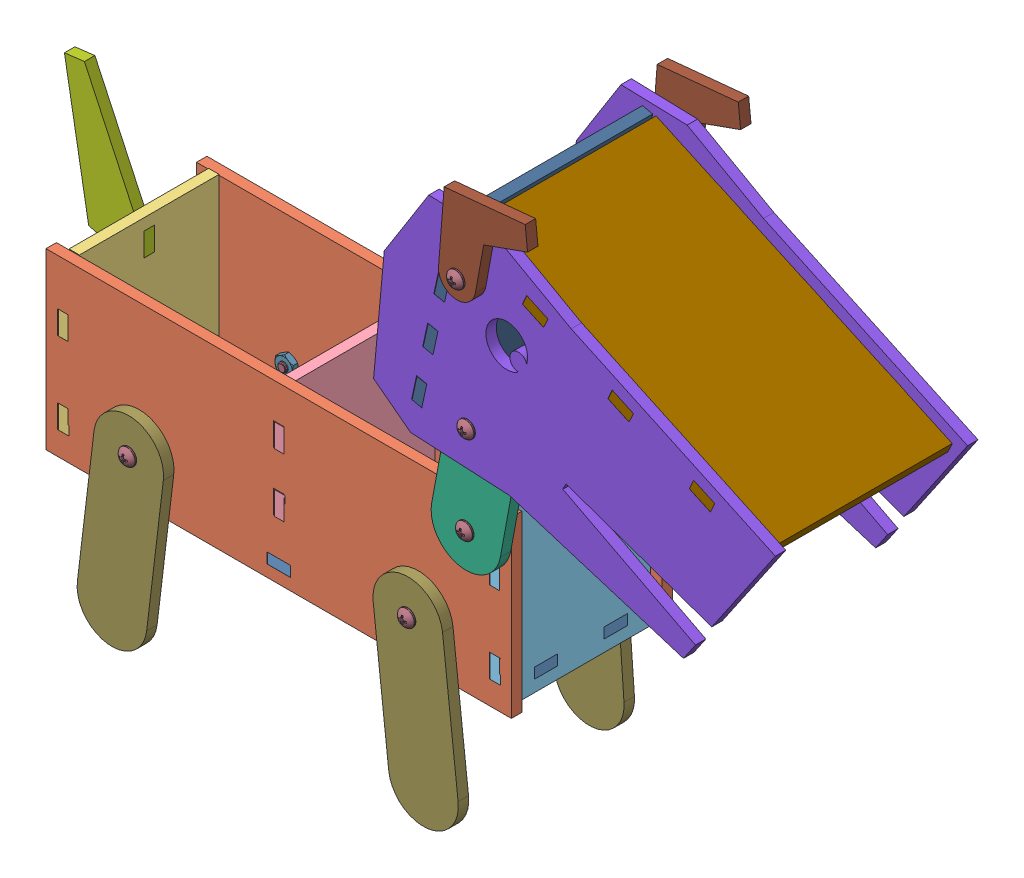
SolidWorks assembly Doggie Lamp, configuration Default. Lengths in mm.
Overall size (449.3 333.43 128.68).
39 component instances, 14 part files, 85 mates.
Components (placement in the parent):
- Bottom-2: Bottom [Default] at (-28.2782 -5.676 3.5153) size (241.25 5.69 87.58)
- Body Sides-5: Body Sides [Default] at (-28.7862 51.4486 41.6153) x (1 0 0) z (0 -1 0) size (254 5.69 95.09)
- Body Sides-6: Body Sides [Default] at (-28.5322 51.4486 -40.2743) x (1 0 0) z (0 -1 0) size (254 5.69 95.09)
- Back-2: Back [Default] at (-143.2132 51.474 3.5153) x (0 0 1) z (0 -1 0) size (87.58 5.69 95.5)
- Middle-2: Middle [Default] at (-25.4334 57.1636 3.5153) x (0 0 1) z (0 -1 0) size (87.58 5.69 89.26)
- Front-2: Front [Default] at (92.3464 51.4486 3.5153) x (0 0 1) z (0 -1 0) size (87.58 5.69 95.5)
- Neck-3: Neck [Default] at (91.28 126.961 -45.9639) x (0.98334 -0.181777 0) z (-0.181777 -0.98334 0) size (38.1 5.69 88.9)
- Neck-4: Neck [Default] at (79.2344 63.1735 52.9945) x (0.98334 -0.181777 0) z (0.181777 0.98334 0) size (38.1 5.69 88.9)
- Tail-1: Tail [Default] at (-148.9028 70.778 0.6705) x (1 0 0) z (0 -1 0) size (43.46 5.69 82.95)
- Head-1: Head [Default] at (139.8428 140.5016 52.9945) x (0.977251 -0.212085 0) z (-0.212085 -0.977251 0) size (216.62 5.69 123.24)
- Head-2: Head [Default] at (140.0968 140.5016 -51.6535) x (0.977251 -0.212085 0) z (-0.212085 -0.977251 0) size (216.62 5.69 123.24)
- Head Top 2-1: Head Top 2 [Default] at (168.1653 174.1819 3.5153) x (0.909157 -0.416453 0) z (0 0 1) size (177.8 5.69 110.34)
- Head Back-1: Head Back [Default] at (68.5938 156.9044 3.5153) x (0 0 1) z (-0.212085 -0.977251 0) size (110.34 5.69 114.3)
- Ears-3: Ears [Default] at (85.6371 198.1656 58.6841) x (0.98367 -0.179982 0) z (-0.179982 -0.98367 0) size (46.25 5.69 60.22)
- Ears-4: Ears [Default] at (85.8911 198.1656 -57.3431) x (0.98367 -0.179982 0) z (-0.179982 -0.98367 0) size (46.25 5.69 60.22)
- Legs-5: Legs [Default] at (-105.8128 -5.0499 47.3049) x (0.992872 -0.119184 0) z (-0.119184 -0.992872 0) size (38.1 5.69 114.3)
- Legs-6: Legs [Default] at (50.8253 -4.7497 47.3049) x (0.993764 0.111505 0) z (0.111505 -0.993764 0) size (38.1 5.69 114.3)
- Legs-7: Legs [Default] at (50.3495 -4.8722 -45.9639) x (0.997441 0.071495 0) z (0.071495 -0.997441 0) size (38.1 5.69 114.3)
- Legs-8: Legs [Default] at (-105.0938 -5.0649 -45.9639) x (0.995565 -0.094071 0) z (-0.094071 -0.995565 0) size (38.1 5.69 114.3)
- Bolt-1: Bolt [90279A830] at (-104.9862 13.3486 37.1195) size (9.12 9.12 19.48)
- Nut-1: Nut [90545A111] at (-104.9862 13.3486 41.6153) size (9.53 11 3.7)
- Bolt-2: Bolt [90279A830] at (-104.7322 13.3486 -30.0889) x (-0.714681 0.699451 0) z (0 0 -1) size (9.12 9.12 19.48)
- Bolt-3: Bolt [90279A830] at (47.6678 13.3486 -30.0889) x (-0.97579 0.218712 0) z (0 0 -1) size (9.12 9.12 19.48)
- Bolt-4: Bolt [90279A830] at (47.4138 13.3486 37.1195) size (9.12 9.12 19.48)
- Nut-2: Nut [90545A111] at (47.6678 13.3486 -31.4097) size (9.53 11 3.7)
- Nut-3: Nut [90545A111] at (47.4138 13.3486 41.6153) size (9.53 11 3.7)
- Nut-4: Nut [90545A111] at (-104.7322 13.3486 -31.4097) size (9.53 11 3.7)
- Bolt-5: Bolt [90279A830] at (79.1638 70.3398 37.1195) size (9.12 9.12 19.48)
- Bolt-6: Bolt [90279A830] at (79.4178 70.3398 -30.0889) x (0.016738 -0.99986 0) z (0 0 -1) size (9.12 9.12 19.48)
- Nut-5: Nut [90545A111] at (79.4178 70.3398 -31.4097) size (9.53 11 3.7)
- Nut-6: Nut [90545A111] at (79.1638 70.3398 41.6153) size (9.53 11 3.7)
- Bolt-7: Bolt [90279A830] at (85.8422 124.4841 -35.7785) x (-0.858966 0.512033 0) z (0 0 -1) size (9.12 9.12 19.48)
- Nut-7: Nut [90545A111] at (85.8422 124.4841 -37.0993) size (9.53 11 3.7)
- Bolt-8: Bolt [90279A830] at (85.5882 124.4841 42.8091) size (9.12 9.12 19.48)
- Nut-8: Nut [90545A111] at (85.5882 124.4841 47.3049) size (9.53 11 3.7)
- Bolt-9: Bolt [90279A830] at (85.6371 198.1656 48.4987) size (9.12 9.12 19.48)
- Nut-9: Nut [90545A111] at (85.6371 198.1656 52.9945) size (9.53 11 3.7)
- Bolt-10: Bolt [90279A830] at (85.8911 198.1656 -41.4681) x (0.959763 0.280811 0) z (0 0 -1) size (9.12 9.12 19.48)
- Nut-10: Nut [90545A111] at (85.8911 198.1656 -42.7889) size (9.53 11 3.7)
Mates (geometry in assembly coordinates):
- Coincident44: coincident anti-aligned: plane of Bottom-2 through (-35.0092 0.0136 41.6153) normal (0 0 1); plane of Body Sides-5 through (-155.7862 114.9486 41.6153) normal (0 0 -1)
- Coincident45: coincident anti-aligned: plane of Bottom-2 through (-101.8112 0.0136 41.6153) normal (-1 0 0); plane of Body Sides-5 through (-101.8112 -5.7014 47.3049) normal (1 0 0)
- Coincident46: coincident anti-aligned: plane of Bottom-2 through (-143.2132 0.0136 -34.5847) normal (0 1 0); plane of Body Sides-5 through (-101.8112 0.0136 47.3049) normal (0 -1 0)
- Coincident47: coincident anti-aligned: plane of Bottom-2 through (-101.8112 0.0136 -34.5847) normal (0 0 -1); plane of Body Sides-6 through (-155.5322 114.9486 -34.5847) normal (0 0 1)
- Coincident48: coincident anti-aligned: plane of Bottom-2 through (44.4928 0.0136 -34.5847) normal (1 0 0); plane of Body Sides-6 through (44.4928 -5.7014 -34.5847) normal (-1 0 0)
- Coincident49: coincident anti-aligned: plane of Bottom-2 through (-143.2132 0.0136 -34.5847) normal (0 1 0); plane of Body Sides-6 through (44.4928 0.0136 -34.5847) normal (0 -1 0)
- Coincident50: coincident anti-aligned: plane of Bottom-2 through (-143.2132 0.0136 16.2153) normal (-1 0 0); plane of Back-2 through (-143.2132 114.974 -34.5847) normal (1 0 0)
- Coincident51: coincident anti-aligned: plane of Bottom-2 through (-143.2132 -5.676 -34.5847) normal (0 -1 0); plane of Back-2 through (-148.9028 -5.676 -21.8847) normal (0 1 0)
- Coincident52: coincident anti-aligned: plane of Bottom-2 through (-143.2132 0.0136 -9.1847) normal (0 0 1); plane of Back-2 through (-148.9028 0.039 -9.1847) normal (0 0 -1)
- Coincident53: coincident anti-aligned: plane of Bottom-2 through (-143.2132 0.0136 -34.5847) normal (0 1 0); plane of Middle-2 through (-31.123 0.0136 41.6153) normal (0 -1 0)
- Coincident54: coincident anti-aligned: plane of Bottom-2 through (-25.4334 0.0136 9.8653) normal (-1 0 0); plane of Middle-2 through (-25.4334 114.3136 -34.5847) normal (1 0 0)
- Coincident55: coincident anti-aligned: plane of Bottom-2 through (-31.123 0.0136 9.8653) normal (0 0 -1); plane of Middle-2 through (-31.123 0.0136 9.8653) normal (0 0 1)
- Coincident56: coincident anti-aligned: plane of Bottom-2 through (86.6568 0.0136 16.2153) normal (1 0 0); plane of Front-2 through (86.6568 114.9486 -34.5847) normal (-1 0 0)
- Coincident57: coincident anti-aligned: plane of Bottom-2 through (-143.2132 0.0136 -34.5847) normal (0 1 0); plane of Front-2 through (86.6568 0.0136 -21.8847) normal (0 -1 0)
- Coincident58: coincident anti-aligned: plane of Body Sides-6 through (-155.5322 114.9486 -34.5847) normal (0 0 1); plane of Front-2 through (86.6568 57.7986 -34.5847) normal (0 0 -1)
- Coincident59: coincident anti-aligned: plane of Body Sides-6 through (-155.5322 114.9486 -40.2743) normal (0 0 -1); plane of Neck-3 through (88.6521 120.2935 -40.2743) normal (0 0 1)
- Coincident60: coincident anti-aligned: plane of Body Sides-5 through (-155.7862 114.9486 47.3049) normal (0 0 1); plane of Neck-4 through (79.1638 70.3398 47.3049) normal (0 0 -1)
- Parallel1: parallel aligned: plane of Neck-3 through (60.6852 73.8027 -40.2743) normal (-0.98334 0.181777 0); plane of Neck-4 through (69.6655 123.7564 47.3049) normal (-0.98334 0.181777 0)
- Coincident62: coincident anti-aligned: plane of Back-2 through (-148.9028 114.974 -34.5847) normal (-1 0 0); plane of Tail-1 through (-148.9028 77.128 6.3601) normal (1 0 0)
- Coincident63: coincident anti-aligned: plane of Back-2 through (-143.2132 77.128 6.3601) normal (0 0 -1); plane of Tail-1 through (-143.2132 64.428 6.3601) normal (0 0 1)
- Coincident64: coincident anti-aligned: plane of Back-2 through (-143.2132 64.428 0.6705) normal (0 1 0); plane of Tail-1 through (-148.9028 64.428 6.3601) normal (0 -1 0)
- Coincident65: coincident anti-aligned: plane of Neck-4 through (79.1638 70.3398 52.9945) normal (0 0 1); plane of Head-1 through (-102.7515 180.5017 52.9945) normal (0 0 -1)
- Coincident66: coincident anti-aligned: plane of Neck-3 through (88.6521 120.2935 -45.9639) normal (0 0 -1); plane of Head-2 through (-102.4975 180.5017 -45.9639) normal (0 0 1)
- Parallel2: parallel aligned: plane of Head-1 through (38.5262 167.5336 58.6841) normal (-0.995814 0.091407 0); plane of Head-2 through (38.7802 167.5336 -45.9639) normal (-0.995814 0.091407 0)
- Coincident72: coincident anti-aligned: plane of Head-1 through (-55.7889 283.0255 58.6841) normal (-0.416453 -0.909157 0); plane of Head Top 2-1 through (83.9375 219.0218 -45.9639) normal (0.416453 0.909157 0)
- Coincident73: coincident anti-aligned: plane of Head-1 through (173.6831 53.8768 58.6841) normal (-0.909157 0.416453 0); plane of Head Top 2-1 through (220.6456 156.4006 52.9945) normal (0.909157 -0.416453 0)
- Coincident74: coincident anti-aligned: plane of Head-1 through (-102.7515 180.5017 52.9945) normal (0 0 -1); plane of Head Top 2-1 through (209.0994 161.6896 52.9945) normal (0 0 1)
- Coincident75: coincident anti-aligned: plane of Head-2 through (60.2287 145.1865 -45.9639) normal (0.977251 -0.212085 0); plane of Head Back-1 through (76.5011 220.1666 -45.9639) normal (-0.977251 0.212085 0)
- Coincident76: coincident anti-aligned: plane of Head-2 through (-102.4975 180.5017 -45.9639) normal (0 0 1); plane of Head Back-1 through (58.0827 135.2982 -45.9639) normal (0 0 -1)
- Coincident77: coincident anti-aligned: plane of Head-2 through (-92.4689 226.7116 -45.9639) normal (-0.212085 -0.977251 0); plane of Head Back-1 through (70.2573 191.3963 -45.9639) normal (0.212085 0.977251 0)
- Coincident78: coincident anti-aligned: plane of Head-1 through (-102.7515 180.5017 58.6841) normal (0 0 1); plane of Ears-3 through (85.6371 198.1656 58.6841) normal (0 0 -1)
- Concentric9: concentric aligned: cylinder of Head-1 through (85.6371 198.1656 58.6841) axis (0 0 -1) radius 2.413; cylinder of Ears-3 through (85.6371 198.1656 64.3737) axis (0 0 -1) radius 2.413
- Coincident79: coincident anti-aligned: plane of Head-2 through (-102.4975 180.5017 -51.6535) normal (0 0 -1); plane of Ears-4 through (85.8911 198.1656 -51.6535) normal (0 0 1)
- Concentric10: concentric aligned: cylinder of Head-2 through (85.8911 198.1656 -45.9639) axis (0 0 -1) radius 2.413; cylinder of Ears-4 through (85.8911 198.1656 -51.6535) axis (0 0 -1) radius 2.413
- Parallel3: parallel aligned: plane of Ears-3 through (75.6431 199.9942 64.3737) normal (-0.996994 0.077481 0); plane of Ears-4 through (75.8971 199.9942 -51.6535) normal (-0.996994 0.077481 0)
- Coincident81: coincident anti-aligned: plane of Body Sides-5 through (-155.7862 114.9486 47.3049) normal (0 0 1); plane of Legs-5 through (-104.9862 13.3486 47.3049) normal (0 0 -1)
- Concentric11: concentric anti-aligned: cylinder of Body Sides-5 through (-104.9862 13.3486 47.3049) axis (0 0 -1) radius 2.413; cylinder of Legs-5 through (-104.9862 13.3486 47.3049) axis (0 0 1) radius 2.413
- Concentric12: concentric anti-aligned: cylinder of Body Sides-5 through (47.4138 13.3486 47.3049) axis (0 0 -1) radius 2.413; cylinder of Legs-6 through (47.4138 13.3486 47.3049) axis (0 0 1) radius 2.413
- Coincident82: coincident anti-aligned: plane of Body Sides-5 through (-155.7862 114.9486 47.3049) normal (0 0 1); plane of Legs-6 through (47.4138 13.3486 47.3049) normal (0 0 -1)
- Coincident83: coincident anti-aligned: plane of Body Sides-6 through (-155.5322 114.9486 -40.2743) normal (0 0 -1); plane of Legs-7 through (47.6678 13.3486 -40.2743) normal (0 0 1)
- Concentric13: concentric anti-aligned: cylinder of Body Sides-6 through (47.6678 13.3486 -34.5847) axis (0 0 -1) radius 2.413; cylinder of Legs-7 through (47.6678 13.3486 -45.9639) axis (0 0 1) radius 2.413
- Coincident84: coincident anti-aligned: plane of Body Sides-6 through (-155.5322 114.9486 -40.2743) normal (0 0 -1); plane of Legs-8 through (-104.7322 13.3486 -40.2743) normal (0 0 1)
- Concentric14: concentric anti-aligned: cylinder of Body Sides-6 through (-104.7322 13.3486 -34.5847) axis (0 0 -1) radius 2.413; cylinder of Legs-8 through (-104.7322 13.3486 -45.9639) axis (0 0 1) radius 2.413
- Concentric15: concentric aligned: cylinder of Body Sides-6 through (79.4178 70.3398 -40.2743) axis (0 0 1) radius 2.413; cylinder of Neck-3 through (79.4178 70.3398 -45.9639) axis (0 0 1) radius 2.413
- Concentric16: concentric anti-aligned: cylinder of Body Sides-5 through (79.1638 70.3398 41.6153) axis (0 0 1) radius 2.413; cylinder of Neck-4 through (79.1638 70.3398 52.9945) axis (0 0 -1) radius 2.413
- Coincident86: coincident anti-aligned: plane of Legs-5 through (-104.9862 13.3486 52.9945) normal (0 0 1); plane of Bolt-1 through (-104.9862 13.3486 52.9945) normal (0 0 -1)
- Concentric18: concentric aligned: cylinder of Legs-5 through (-104.9862 13.3486 47.3049) axis (0 0 1) radius 2.413; cylinder of Bolt-1 through (-104.9862 13.3486 37.1195) axis (0 0 1) radius 2.413
- Concentric19: concentric anti-aligned: cylinder of Bolt-1 through (-104.9862 13.3486 37.1195) axis (0 0 1) radius 2.413; cylinder of Nut-1 through (-104.9862 13.3486 41.6153) axis (0 0 -1) radius 1.8974
- Coincident87: coincident anti-aligned: plane of Body Sides-5 through (-155.7862 114.9486 41.6153) normal (0 0 -1); plane of Nut-1 through (-100.2237 16.0982 41.6153) normal (0 0 1)
- Coincident88: coincident anti-aligned: plane of Legs-8 through (-104.7322 13.3486 -45.9639) normal (0 0 -1); plane of Bolt-2 through (-104.7322 13.3486 -45.9639) normal (0 0 1)
- Concentric20: concentric anti-aligned: cylinder of Legs-8 through (-104.7322 13.3486 -45.9639) axis (0 0 1) radius 2.413; cylinder of Bolt-2 through (-104.7322 13.3486 -30.0889) axis (0 0 -1) radius 2.413
- Coincident89: coincident anti-aligned: plane of Legs-7 through (47.6678 13.3486 -45.9639) normal (0 0 -1); plane of Bolt-3 through (47.6678 13.3486 -45.9639) normal (0 0 1)
- Concentric21: concentric anti-aligned: cylinder of Legs-7 through (47.6678 13.3486 -45.9639) axis (0 0 1) radius 2.413; cylinder of Bolt-3 through (47.6678 13.3486 -30.0889) axis (0 0 -1) radius 2.413
- Coincident90: coincident anti-aligned: plane of Legs-6 through (47.4138 13.3486 52.9945) normal (0 0 1); plane of Bolt-4 through (47.4138 13.3486 52.9945) normal (0 0 -1)
- Concentric22: concentric aligned: cylinder of Legs-6 through (47.4138 13.3486 47.3049) axis (0 0 1) radius 2.413; cylinder of Bolt-4 through (47.4138 13.3486 37.1195) axis (0 0 1) radius 2.413
- Concentric23: concentric aligned: cylinder of Bolt-3 through (47.6678 13.3486 -30.0889) axis (0 0 -1) radius 2.413; cylinder of Nut-2 through (47.6678 13.3486 -31.4097) axis (0 0 -1) radius 1.8974
- Coincident91: coincident anti-aligned: plane of Body Sides-6 through (-155.5322 114.9486 -34.5847) normal (0 0 1); plane of Nut-2 through (52.4303 16.0982 -34.5847) normal (0 0 -1)
- Concentric24: concentric aligned: cylinder of Bolt-4 through (47.4138 13.3486 37.1195) axis (0 0 1) radius 2.413; cylinder of Nut-3 through (47.4138 13.3486 38.4403) axis (0 0 1) radius 2.413
- Coincident92: coincident anti-aligned: plane of Body Sides-5 through (-155.7862 114.9486 41.6153) normal (0 0 -1); plane of Nut-3 through (52.1763 16.0982 41.6153) normal (0 0 1)
- Concentric25: concentric aligned: cylinder of Bolt-2 through (-104.7322 13.3486 -30.0889) axis (0 0 -1) radius 2.413; cylinder of Nut-4 through (-104.7322 13.3486 -31.4097) axis (0 0 -1) radius 1.8974
- Coincident93: coincident anti-aligned: plane of Body Sides-6 through (-155.5322 114.9486 -34.5847) normal (0 0 1); plane of Nut-4 through (-99.9697 16.0982 -34.5847) normal (0 0 -1)
- Coincident94: coincident anti-aligned: plane of Neck-4 through (79.1638 70.3398 52.9945) normal (0 0 1); plane of Bolt-5 through (79.1638 70.3398 52.9945) normal (0 0 -1)
- Concentric26: concentric anti-aligned: cylinder of Neck-4 through (79.1638 70.3398 52.9945) axis (0 0 -1) radius 2.413; cylinder of Bolt-5 through (79.1638 70.3398 37.1195) axis (0 0 1) radius 2.413
- Coincident95: coincident anti-aligned: plane of Neck-3 through (88.6521 120.2935 -45.9639) normal (0 0 -1); plane of Bolt-6 through (79.4178 70.3398 -45.9639) normal (0 0 1)
- Concentric27: concentric anti-aligned: cylinder of Neck-3 through (79.4178 70.3398 -45.9639) axis (0 0 1) radius 2.413; cylinder of Bolt-6 through (79.4178 70.3398 -30.0889) axis (0 0 -1) radius 2.413
- Coincident96: coincident anti-aligned: plane of Body Sides-6 through (-155.5322 114.9486 -34.5847) normal (0 0 1); plane of Nut-5 through (84.1803 73.0895 -34.5847) normal (0 0 -1)
- Concentric29: concentric aligned: cylinder of Bolt-6 through (79.4178 70.3398 -30.0889) axis (0 0 -1) radius 2.413; cylinder of Nut-5 through (79.4178 70.3398 -31.4097) axis (0 0 -1) radius 1.8974
- Coincident97: coincident anti-aligned: plane of Body Sides-5 through (-155.7862 114.9486 41.6153) normal (0 0 -1); plane of Nut-6 through (83.9263 73.0895 41.6153) normal (0 0 1)
- Concentric30: concentric anti-aligned: cylinder of Bolt-5 through (79.1638 70.3398 37.1195) axis (0 0 1) radius 2.413; cylinder of Nut-6 through (79.1638 70.3398 41.6153) axis (0 0 -1) radius 1.8974
- Coincident98: coincident anti-aligned: plane of Head-2 through (-102.4975 180.5017 -51.6535) normal (0 0 -1); plane of Bolt-7 through (85.8422 124.4841 -51.6535) normal (0 0 1)
- Concentric31: concentric aligned: cylinder of Head-2 through (85.8422 124.4841 -45.9639) axis (0 0 -1) radius 2.413; cylinder of Bolt-7 through (85.8422 124.4841 -35.7785) axis (0 0 -1) radius 2.413
- Concentric32: concentric aligned: cylinder of Bolt-7 through (85.8422 124.4841 -35.7785) axis (0 0 -1) radius 2.413; cylinder of Nut-7 through (85.8422 124.4841 -37.0993) axis (0 0 -1) radius 1.8974
- Coincident99: coincident anti-aligned: plane of Neck-3 through (88.6521 120.2935 -40.2743) normal (0 0 1); plane of Nut-7 through (90.6047 127.2338 -40.2743) normal (0 0 -1)
- Coincident100: coincident anti-aligned: plane of Head-1 through (-102.7515 180.5017 58.6841) normal (0 0 1); plane of Bolt-8 through (85.5882 124.4841 58.6841) normal (0 0 -1)
- Concentric33: concentric anti-aligned: cylinder of Head-1 through (85.5882 124.4841 58.6841) axis (0 0 -1) radius 2.413; cylinder of Bolt-8 through (85.5882 124.4841 42.8091) axis (0 0 1) radius 2.413
- Concentric34: concentric anti-aligned: cylinder of Bolt-8 through (85.5882 124.4841 42.8091) axis (0 0 1) radius 2.413; cylinder of Nut-8 through (85.5882 124.4841 47.3049) axis (0 0 -1) radius 1.8974
- Coincident101: coincident anti-aligned: plane of Neck-4 through (79.1638 70.3398 47.3049) normal (0 0 -1); plane of Nut-8 through (90.3507 127.2338 47.3049) normal (0 0 1)
- Coincident102: coincident anti-aligned: plane of Ears-3 through (85.6371 198.1656 64.3737) normal (0 0 1); plane of Bolt-9 through (85.6371 198.1656 64.3737) normal (0 0 -1)
- Concentric35: concentric anti-aligned: cylinder of Ears-3 through (85.6371 198.1656 64.3737) axis (0 0 -1) radius 2.413; cylinder of Bolt-9 through (85.6371 198.1656 48.4987) axis (0 0 1) radius 2.413
- Concentric36: concentric anti-aligned: cylinder of Bolt-9 through (85.6371 198.1656 48.4987) axis (0 0 1) radius 2.413; cylinder of Nut-9 through (85.6371 198.1656 52.9945) axis (0 0 -1) radius 1.8974
- Coincident103: coincident anti-aligned: plane of Head-1 through (-102.7515 180.5017 52.9945) normal (0 0 -1); plane of Nut-9 through (90.3996 200.9152 52.9945) normal (0 0 1)
- Coincident104: coincident anti-aligned: plane of Ears-4 through (85.8911 198.1656 -57.3431) normal (0 0 -1); plane of Bolt-10 through (85.8911 198.1656 -57.3431) normal (0 0 1)
- Concentric37: concentric aligned: cylinder of Ears-4 through (85.8911 198.1656 -51.6535) axis (0 0 -1) radius 2.413; cylinder of Bolt-10 through (85.8911 198.1656 -41.4681) axis (0 0 -1) radius 2.413
- Concentric38: concentric anti-aligned: cylinder of Bolt-10 through (85.8911 198.1656 -41.4681) axis (0 0 -1) radius 2.413; cylinder of Nut-10 through (85.8911 198.1656 -45.9639) axis (0 0 1) radius 2.413
- Coincident105: coincident anti-aligned: plane of Head-2 through (-102.4975 180.5017 -45.9639) normal (0 0 1); plane of Nut-10 through (90.6536 200.9152 -45.9639) normal (0 0 -1)
